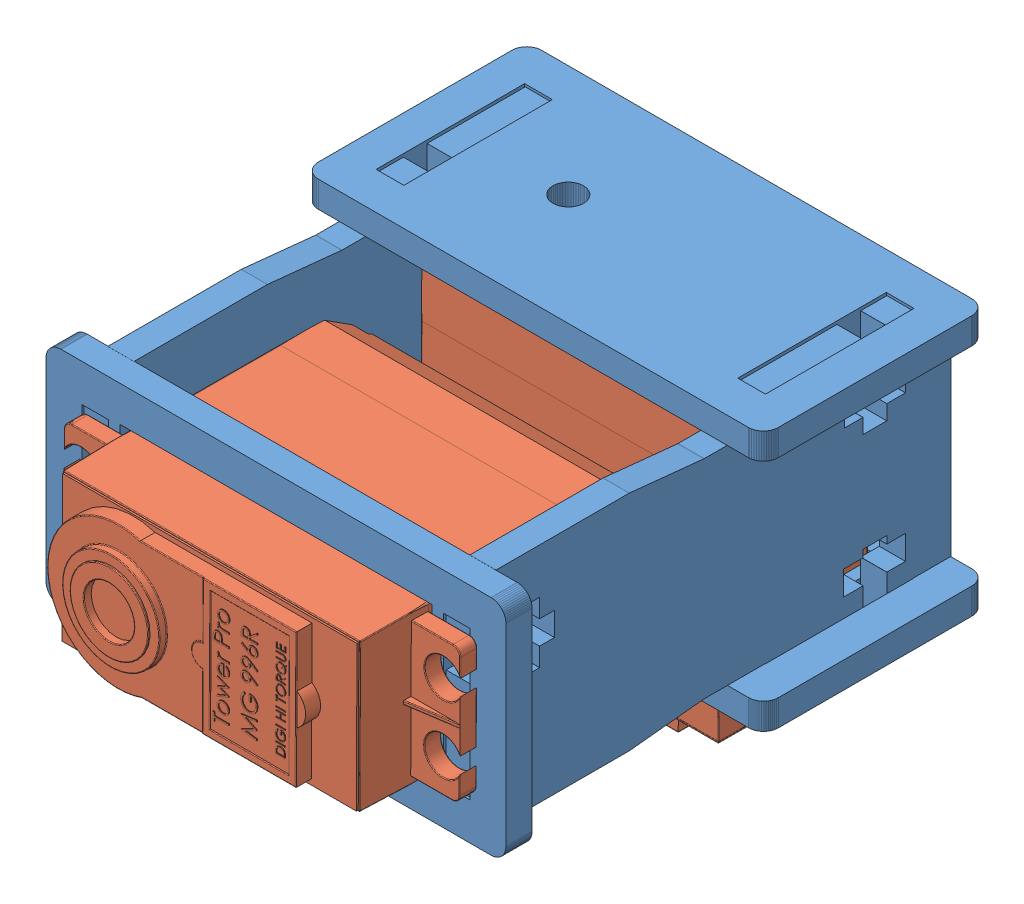
SolidWorks assembly left_upper_arm, configuration Default. Lengths in mm.
Overall size (61.53 47.32 76.93).
5 component instances, 2 part files, 2 mates.
Components (placement in the parent):
- left_upper_arm_100-1: left_upper_arm_100 [Default] at (-18.1337 8.0588 24.0594) size (61.53 34.82 64.34)
- main_assembly-1: main_assembly [Default] at (46.9138 17.2854 29.8664) x (0 0.999989 -0.004644) z (0 0.004644 0.999989) size (20 53 41.5)
  - main_body-1: main_body [Default] at (15.1003 34.2066 38.7045) size (20 53 41.5)
- main_assembly-2: main_assembly [Default] at (46.1759 73.7689 23.5233) x (0 0.004665 0.999989) z (0 -0.999989 0.004665) size (20 53 41.5)
  - main_body-1: main_body [Default] at (15.1003 34.2066 38.7045) size (20 53 41.5)
Mates (geometry in assembly coordinates):
- Coincident1: coincident anti-aligned: line of left_upper_arm_100-1 through (-8.5512 42.6581 88.4537) axis (1 0 0); line of main_assembly-1/main_body-1 through (32.4572 42.6581 88.4537) axis (-1 0 0)
- Coincident2: coincident anti-aligned: line of left_upper_arm_100-1 through (33.1551 15.0889 28.8974) axis (-1 0 0); line of main_assembly-2/main_body-1 through (-7.7807 15.0889 28.8974) axis (1 0 0)
